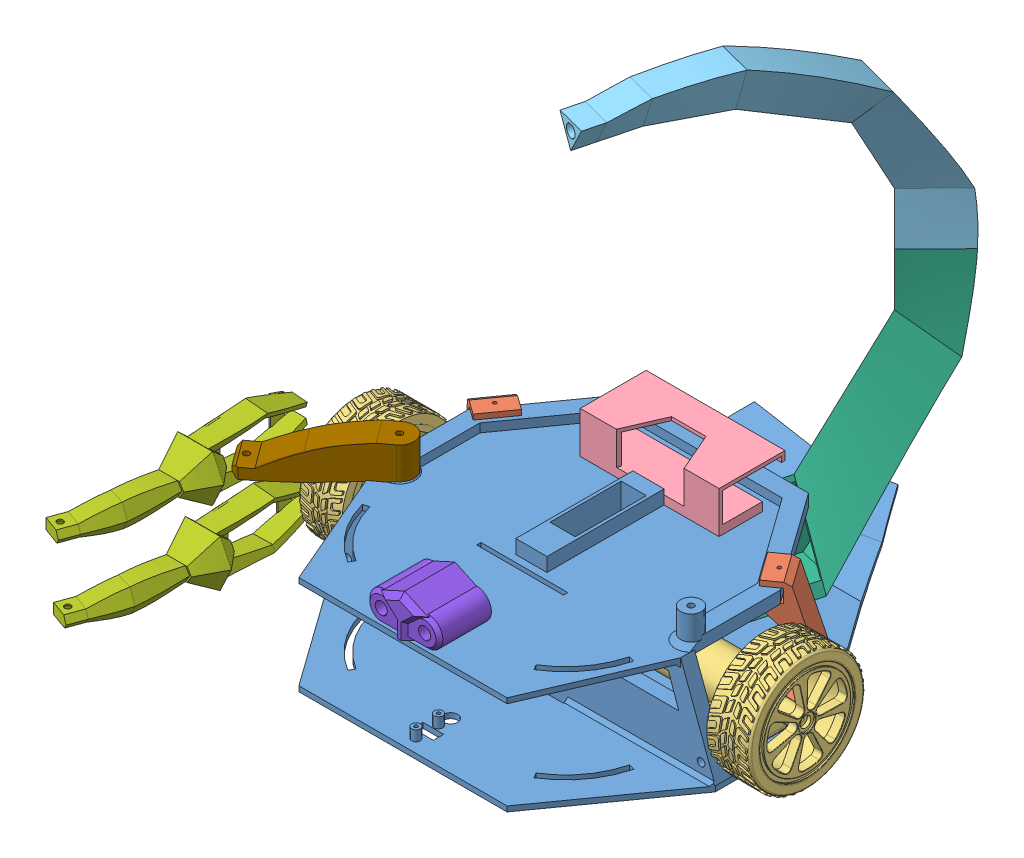
SolidWorks assembly Assem1, configuration Default. Lengths in mm.
Overall size (315.41 289.21 310.29).
12 component instances, 9 part files, 21 mates.
Components (placement in the parent):
- Base-1: Base [Default] at (-82.1693 -50.6311 72.6618) size (220 74 248.08)
- base_reforço-1: base_reforço [Default] at (-6.3564 -51.1311 35.0193) x (0.813733 0 -0.581238) z (0.581238 0 0.813733) size (31.62 69.7 20)
- Ass_Motor-1: Ass_Motor [Default] at (-68.1554 -37.2622 163.1044) x (0 0 1) z (1 0 0) size (68.01 68.01 88)
- Ass_Motor-2: Ass_Motor [Default] at (-98.1832 -37.2622 -17.7807) x (0 0 -1) z (-1 0 0) size (68.01 68.01 88)
- base_reforço-2: base_reforço [Default] at (-168.0929 -50.6311 51.5462) x (-0.813733 0 -0.581238) z (0.581238 0 -0.813733) size (31.62 69.7 20)
- bat_holder-1: bat_holder [Default] at (-41.5102 6.3689 10.1618) x (-1 0 0) z (0 0 -1) size (80 24 38)
- cauda_1-1: cauda_1 [Default] at (-80.6543 -20.4466 66.8563) x (0.25251 0 -0.967594) z (0.967594 0 0.25251) size (182.83 123.75 33.68)
- Cauda_2-1: Cauda_2 [Default] at (-80.6543 -20.4466 66.8563) x (0.25251 0 -0.967594) z (0.967594 0 0.25251) size (183.19 140.4 51.96)
- garra-1: garra [Default] at (-252.5087 -19.7239 116.1044) size (32.5 29.53 133.95)
- garra-2: garra [Default] at (-243.2096 -54.9842 121.0051) size (32.5 29.53 133.95)
- head-1: head [Default] at (-82.1988 14.8689 176.6618) x (-1 0 0) z (0 0 -1) size (42 22.75 32)
- patinha-1: patinha [Default] at (-166.1693 25.3689 94.6618) x (0.805545 0 -0.592535) z (-0.592535 0 -0.805545) size (76.7 24.06 19.92)
Mates (geometry in assembly coordinates):
- Distance1: distance = 0.5 mm anti-aligned: plane of Base-1 through (-82.1693 -50.6311 72.6618) normal (0 -1 0); plane of base_reforço-1 through (5.2683 -51.1311 51.2939) normal (0 1 0)
- Coincident2: coincident anti-aligned: plane of Base-1 through (27.8307 -47.6311 42.6618) normal (0.813733 0 -0.581238); plane of base_reforço-1 through (24.291 -51.1311 37.7063) normal (-0.813733 0 0.581238)
- Coincident3: coincident anti-aligned: plane of Base-1 through (-82.1693 6.3689 72.6618) normal (0 1 0); plane of bat_holder-1 through (-41.5102 6.3689 10.1618) normal (0 -1 0)
- Coincident4: coincident anti-aligned: plane of Base-1 through (-73.1693 -11.6311 35.1618) normal (0 0 -1); plane of bat_holder-1 through (-41.5102 11.3689 35.1618) normal (0 0 1)
- Coincident7: coincident anti-aligned: plane of Base-1 through (-131.877 6.3689 -7.3382) normal (-0.813733 0 -0.581238); plane of base_reforço-2 through (-160.338 13.0689 32.5073) normal (0.813733 0 0.581238)
- Coincident8: coincident anti-aligned: plane of Base-1 through (-82.1693 -50.6311 72.6618) normal (0 -1 0); plane of base_reforço-2 through (-156.4682 -50.6311 35.2715) normal (0 1 0)
- Coincident11: coincident anti-aligned: plane of Base-1 through (-82.1693 -47.6311 72.6618) normal (0 1 0); plane of Ass_Motor-2 through (-152.1693 -47.6311 85.6618) normal (0 -1 0)
- Concentric1: concentric aligned: cylinder of Base-1 through (-159.1693 -46.6311 80.6618) axis (0 -1 0) radius 1.75; cylinder of Ass_Motor-2 through (-159.1693 -21.6311 80.6618) axis (0 -1 0) radius 1.5
- Perpendicular1: perpendicular: plane of Base-1 through (-192.1693 -47.6311 42.6618) normal (-1 0 0); plane of Ass_Motor-2 through (-152.1693 -44.6311 59.6618) normal (0 0 -1)
- Coincident13: coincident anti-aligned: plane of Base-1 through (-82.1693 -47.6311 72.6618) normal (0 1 0); plane of Ass_Motor-1 through (-14.1693 -47.6311 59.6618) normal (0 -1 0)
- Concentric4: concentric aligned: cylinder of Base-1 through (8.8307 -46.6311 64.6618) axis (0 -1 0) radius 1.75; cylinder of Ass_Motor-1 through (8.8307 -21.6311 64.6618) axis (0 -1 0) radius 1.5
- Concentric5: concentric anti-aligned: cylinder of Ass_Motor-1 through (18.8307 -23.6311 72.6618) axis (-1 0 0) radius 12.5; cylinder of Ass_Motor-2 through (-185.1693 -23.6311 72.6618) axis (1 0 0) radius 12.5
- Coincident15: coincident anti-aligned: plane of Base-1 through (-82.1693 -44.6311 72.6618) normal (0 1 0); plane of Cauda_2-1 through (-98.0115 -44.6311 133.3674) normal (0 -1 0)
- Concentric6: concentric aligned: cylinder of Base-1 through (-82.1693 -44.6311 72.6618) axis (0 -1 0) radius 9.2514; cylinder of Cauda_2-1 through (-82.1693 -7.6311 72.6618) axis (0 -1 0) radius 1.75
- Coincident16: coincident: plane of cauda_1-1 through (-45.0807 95.7677 -69.4582) normal (0 -1 0); plane of Cauda_2-1 through (-45.0807 95.7677 -69.4582) normal (0 1 0)
- Coincident17: coincident: point of cauda_1-1; point of Cauda_2-1
- Coincident19: coincident: point of cauda_1-1; point of Cauda_2-1
- Coincident20: coincident: plane of Base-1 through (-82.1693 6.3689 72.6618) normal (0 1 0); plane of head-1 through (-69.6988 6.3689 171.6618) normal (0 -1 0)
- Coincident21: coincident aligned: plane of Base-1 through (-142.1693 3.3689 176.6618) normal (0 0 1); plane of head-1 through (-69.6988 14.8689 176.6618) normal (0 0 1)
- Concentric7: concentric: cylinder of Base-1 through (-166.1693 11.3689 94.6618) axis (0 -1 0) radius 6; cylinder of patinha-1 through (-166.1693 8.3689 94.6618) axis (0 1 0) radius 6.35
- Coincident22: coincident anti-aligned: plane of Base-1 through (-166.1693 23.3689 94.6618) normal (0 1 0); plane of patinha-1 through (-166.1693 23.3689 94.6618) normal (0 -1 0)
